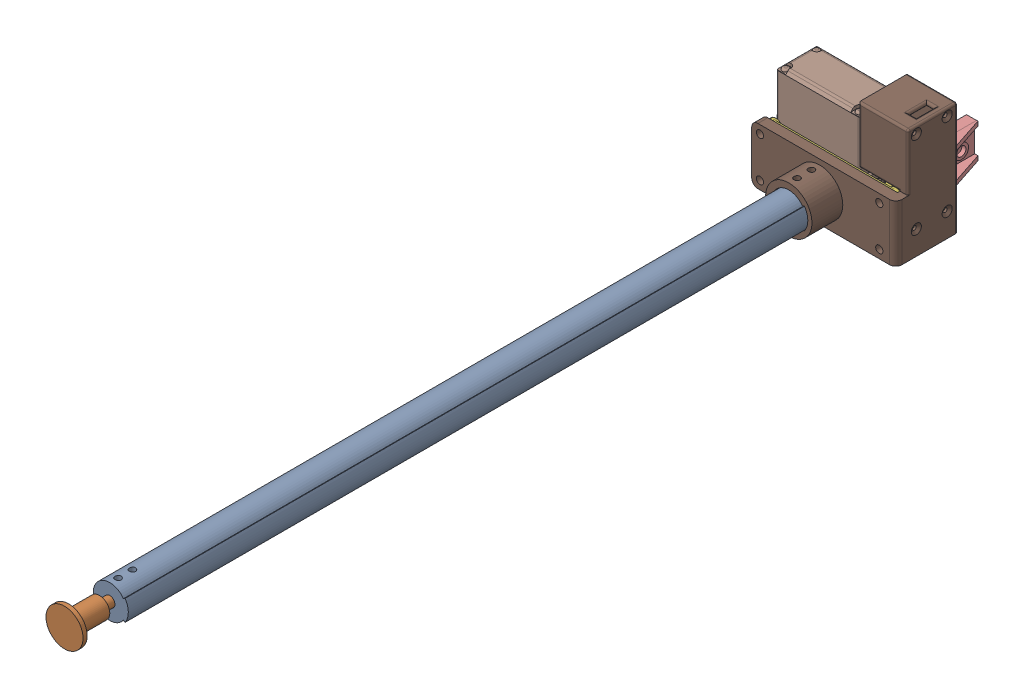
SolidWorks assembly 01-GRIPPER, configuration Default. Lengths in mm.
Overall size (73.53 55.75 426.3).
11 component instances, 11 part files, 0 mates.
Components (placement in the parent):
- Gripper_Arm-1: Gripper_Arm [Default] at (199.6149 0 301) x (1 0 0) z (0 0 1) size (17 16.06 345)
- Gripper_Shaft_Flange-1: Gripper_Shaft_Flange [Default] at (199.6149 0.0639 313) x (1 0 0) z (0 0 1) size (18 18 36.5)
- zz_gripper_left_rod-1: zz_gripper_left_rod [Default] at (333.2811 -8.5 248.4887) x (0.438371 0 0.898794) z (0 -1 0) size (17.89 16.08 3)
- zz_gripper_finger_left-1: zz_gripper_finger_left [Default] at (315.6889 8.4 268.2) x (1 0 0) z (0 0 -1) size (13.5 16.7 45)
- zz_gripper_wheel-1: zz_gripper_wheel [Default] at (349.6889 -6.5 264.0067) x (-0.559193 0 0.829038) z (0 -1 0) size (23 23 8)
- zz_gripper_body-1: zz_gripper_body [Default] at (349.6889 0 318.7) x (1 0 0) z (0 0 -1) size (64 25 26)
- zz_gripper_right_rod-1: zz_gripper_right_rod [Default] at (363.26 -10.5 280.7768) x (0.325568 0 0.945519) z (0 1 0) size (17.89 16.08 3)
- zz_gripper_servo_body-1: zz_gripper_servo_body [Default] at (339.3765 -0.3598 263.2) x (-1 0 0) z (0 0 -1) size (52.83 37.52 19.69)
- zz_gripper_servo_output-2: zz_gripper_servo_output [Default] at (349.6889 -7.9036 263.2) x (-1 0 0) z (0 0 -1) size (5.73 3.92 5.73)
- zz_gripper_finger_right-2: zz_gripper_finger_right [Default] at (383.6889 8.85 268.2) x (1 0 0) z (0 0 -1) size (13.5 16.7 45)
- zz_gripper_flange-2: zz_gripper_flange [Default] at (349.6149 0 277.7) x (1 0 0) z (0 0 1) size (70 55 45)
